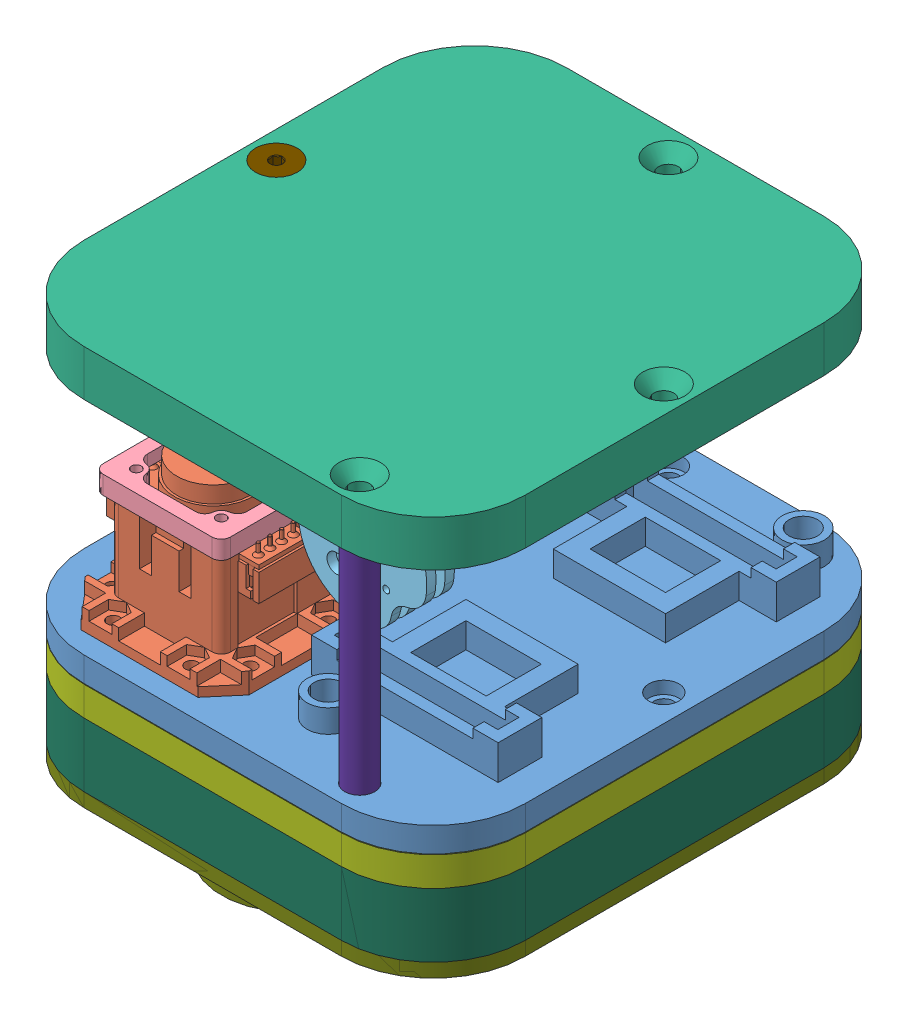
SolidWorks assembly assemtest, configuration Default. Lengths in mm.
Overall size (96 92.27 105).
56 component instances, 18 part files, 3 mates.
Components (placement in the parent):
- wrist_block_final-1: wrist_block_final [Default] at (-50.4615 -58.9787 -69.1823) size (96.58 92.57 105.84)
  - w1-1: w1 [Default] at (-5.748 25.854 -30.7534) size (96 66.92 105)
    - w_t1_test-1: w_t1_test [Default] at (30.6952 9.3465 110.579) size (96 12.88 105)
    - gear_MX-28-1: gear_MX-28 [Default] at (18.9956 62.9761 161.9587) x (-1 0 0) z (0 -1 0) size (35.6 52.23 39.77)
      - dynamixel MX-28-exposed-1: dynamixel MX-28-exposed [Back Off] at (8.6005 39.3797 35.4547) size (35.6 50.6 39.77)
      - w_g1-2: w_g1 [Default] at (8.6005 39.3797 55.9747) size (25.49 25.49 3)
      - w_ac-1: w_ac [Default] at (20.9755 51.5047 26.7047) x (0 -1 0) z (0 0 -1) size (48.25 27.65 4)
    - pulley_MX-28-1: pulley_MX-28 [Default] at (51.4952 51.1215 127.129) size (38.36 58.4 42.92) (hidden)
      - dynamixel MX-28-exposed-1: dynamixel MX-28-exposed [Back Off] at origin size (35.6 50.6 39.77)
      - w_p1-1: w_p1 [Default] at (0 0 23.67) x (0.707107 -0.707107 0) z (0 0 1) size (26.25 28 6)
      - w_ac-1: w_ac [Default] at (12.375 12.125 -8.75) x (0 -1 0) z (0 0 -1) size (48.25 27.65 4)
    - pulley_MX-28-2: pulley_MX-28 [Default] at (51.4952 51.1215 92.029) x (-1 0 0) z (0 0 -1) size (38.36 58.4 42.92) (hidden)
      - dynamixel MX-28-exposed-1: dynamixel MX-28-exposed [Back Off] at origin size (35.6 50.6 39.77)
      - w_p1-1: w_p1 [Default] at (0 0 23.67) x (0.707107 -0.707107 0) z (0 0 1) size (26.25 28 6)
      - w_ac-1: w_ac [Default] at (12.375 12.125 -8.75) x (0 -1 0) z (0 0 -1) size (48.25 27.65 4)
    - pulley_MX-28-3: pulley_MX-28 [Default] at (9.8952 51.1215 92.029) x (-1 0 0) z (0 0 -1) size (38.36 58.4 42.92) (hidden)
      - dynamixel MX-28-exposed-1: dynamixel MX-28-exposed [Back Off] at origin size (35.6 50.6 39.77)
      - w_p1-1: w_p1 [Default] at (0 0 23.67) x (0.707107 -0.707107 0) z (0 0 1) size (26.25 28 6)
      - w_ac-1: w_ac [Default] at (12.375 12.125 -8.75) x (0 -1 0) z (0 0 -1) size (48.25 27.65 4)
    - w_b1-1: w_b1 [Default] at (30.6952 70.6215 113.079) x (-1 0 0) z (0 0 1) size (96 14 105) (hidden)
  - w2-1: w2 [Default] at (-13.7396 -16.4115 -4.4526) size (96 12.03 105)
    - w_t2-1: w_t2 [Default] at (38.6868 42.912 84.2782) size (96 6.36 105)
    - w_g2-1: w_g2 [Default] at (35.3573 46.267 79.3076) x (1 0 0) z (0 1 0) size (25.39 25.39 5.6)
    - w_g3-1: w_g3 [Default] at (71.6818 49.267 106.8682) x (1 0 0) z (0 -1 0) size (25.39 25.39 12.03)
    - w_g2-2: w_g2 [Default] at (48.9868 46.267 99.0621) x (0.999627 0 -0.027307) z (0 1 0) size (25.39 25.39 5.6)
    - w_g3-2: w_g3 [Default] at (49.1868 49.267 59.6927) x (-1 0 0) z (0 -1 0) size (25.39 25.39 12.03)
    - t_b3-1: t_b3 [Default] at (60.3318 38.717 114.6932) x (-1 0 0) z (0 1 0) size (27.89 5.19 4)
    - t_b4-1: t_b4 [Default] at (49.1868 38.717 51.8677) x (1 0 0) z (0 1 0) size (46.79 5.19 4)
    - t_block-1: t_block [Default] at (73.3513 54.116 55.2467) x (0.001081 0.999999 0) z (0.999999 -0.001081 0) size (4.5 3.6 19.7)
      - t_b1-1: t_b1 [Default] at (-13.3027 14.296 -11.9013) size (4.5 3.6 19.7)
      - t_b2-1: t_b2 [Default] at (-13.4027 16.496 -3.3324) x (0.998206 0 0.059878) z (0.059878 0 -0.998206) size (1.9 2 1.9)
    - t_block-2: t_block [Default] at (31.7337 54.161 55.2467) x (0.001081 0.999999 0) z (0.999999 -0.001081 0) size (4.5 3.6 19.7)
      - t_b1-1: t_b1 [Default] at (-13.3027 14.296 -11.9013) size (4.5 3.6 19.7)
      - t_b2-1: t_b2 [Default] at (-13.4027 16.496 -3.3324) x (0.998206 0 0.059878) z (0.059878 0 -0.998206) size (1.9 2 1.9)
    - t_block-3: t_block [Default] at (45.6494 54.1646 118.078) x (0 1 0) z (-1 0 0) size (4.5 3.6 19.7)
      - t_b1-1: t_b1 [Default] at (-13.3027 14.296 -11.9013) size (4.5 3.6 19.7)
      - t_b2-1: t_b2 [Default] at (-13.4027 16.496 -3.3324) x (0.998206 0 0.059878) z (0.059878 0 -0.998206) size (1.9 2 1.9)
    - t_b5-1: t_b5 [Default] at (28.3868 42.912 51.8677) x (-1 0 0) z (0 0 1) size (4 6.8 3.8)
    - t_b5-2: t_b5 [Default] at (69.9868 42.912 51.8677) x (-1 0 0) z (0 0 1) size (4 6.8 3.8)
    - t_b5-3: t_b5 [Default] at (48.9818 42.912 114.6932) x (-1 0 0) z (0 0 1) size (4 6.8 3.8)
  - w_t3-1: w_t3 [Default] at (24.9472 18.9505 82.3256) size (96 13.9 105)
  - w_t4-1: w_t4 [Default] at (50.4615 58.9787 69.1823) size (96 8.4 105) (hidden)
  - al_female_round_standoff-1: al_female_round_standoff [93330A483] at (51.0893 61.0755 128.9678) x (1 0 0) z (0 1 0) size (6.35 6.35 51.38) (hidden)
  - al_female_round_standoff-2: al_female_round_standoff [93330A483] at (-17.195 61.0755 78.8256) x (0.680091 0 -0.733128) z (0 1 0) size (6.35 6.35 51.38) (hidden)
  - al_female_round_standoff-3: al_female_round_standoff [93330A483] at (67.0893 61.0755 78.8256) x (0.546508 0 0.837454) z (0 1 0) size (6.35 6.35 51.38) (hidden)
  - al_female_round_standoff-4: al_female_round_standoff [93330A483] at (24.9472 61.0755 35.6835) x (1 0 0) z (0 1 0) size (6.35 6.35 51.38) (hidden)
  - st_fh_sc_screw_8_32-1: st_fh_sc_screw_8_32 [92210A197] at (-17.195 96.4755 78.8256) x (0.989952 0 -0.141402) z (0 1 0) size (9.12 9.12 19.5) (hidden)
  - st_fh_sc_screw_8_32-2: st_fh_sc_screw_8_32 [92210A197] at (-17.195 27.0005 78.8256) x (0.178781 0 -0.983889) z (0 -1 0) size (9.12 9.12 19.5) (hidden)
  - st_fh_sc_screw_8_32-3: st_fh_sc_screw_8_32 [92210A197] at (51.0893 96.4755 128.9678) x (0.989952 0 -0.141402) z (0 1 0) size (9.12 9.12 19.5) (hidden)
  - st_fh_sc_screw_8_32-4: st_fh_sc_screw_8_32 [92210A197] at (24.9472 96.4755 35.6835) x (0.989952 0 -0.141402) z (0 1 0) size (9.12 9.12 19.5) (hidden)
  - st_fh_sc_screw_8_32-5: st_fh_sc_screw_8_32 [92210A197] at (67.0893 27.0005 78.8256) x (-0.751419 0 -0.659826) z (0 -1 0) size (9.12 9.12 19.5) (hidden)
  - st_fh_sc_screw_8_32-6: st_fh_sc_screw_8_32 [92210A197] at (51.0893 27.0005 128.9678) x (-0.44773 0 0.894169) z (0 -1 0) size (9.12 9.12 19.5) (hidden)
  - st_fh_sc_screw_8_32-7: st_fh_sc_screw_8_32 [92210A197] at (67.0893 96.4755 78.8256) x (0.989952 0 -0.141402) z (0 1 0) size (9.12 9.12 19.5) (hidden)
  - st_fh_sc_screw_8_32-8: st_fh_sc_screw_8_32 [92210A197] at (24.9472 27.0005 35.6835) x (-0.751419 0 -0.659826) z (0 -1 0) size (9.12 9.12 19.5) (hidden)
- w_t3-1: w_t3 [Default] at (-25.5143 -40.0282 13.1434) size (96 13.9 105)
- w_t4-1: w_t4 [Default] at origin size (96 8.4 105)
Mates (geometry in assembly coordinates):
- Coincident1: coincident aligned: plane of wrist_block_final-1/w1-1/w_t1_test-1 through (-25.5143 -20.6032 -39.3566) normal (0 0 -1); plane of w_t3-1 through (-53.5143 -37.0282 -39.3566) normal (0 0 -1)
- Coincident2: coincident aligned: plane of wrist_block_final-1/w2-1/w_t2-1 through (22.4857 -29.3032 10.6434) normal (1 0 0); plane of w_t3-1 through (22.4857 -37.0282 -19.3566) normal (1 0 0)
- Coincident6: coincident anti-aligned: plane of wrist_block_final-1/w2-1/w_t2-1 through (-25.5143 -32.4782 10.6434) normal (0 -1 0); plane of w_t3-1 through (-25.5143 -32.4782 13.1434) normal (0 1 0)
